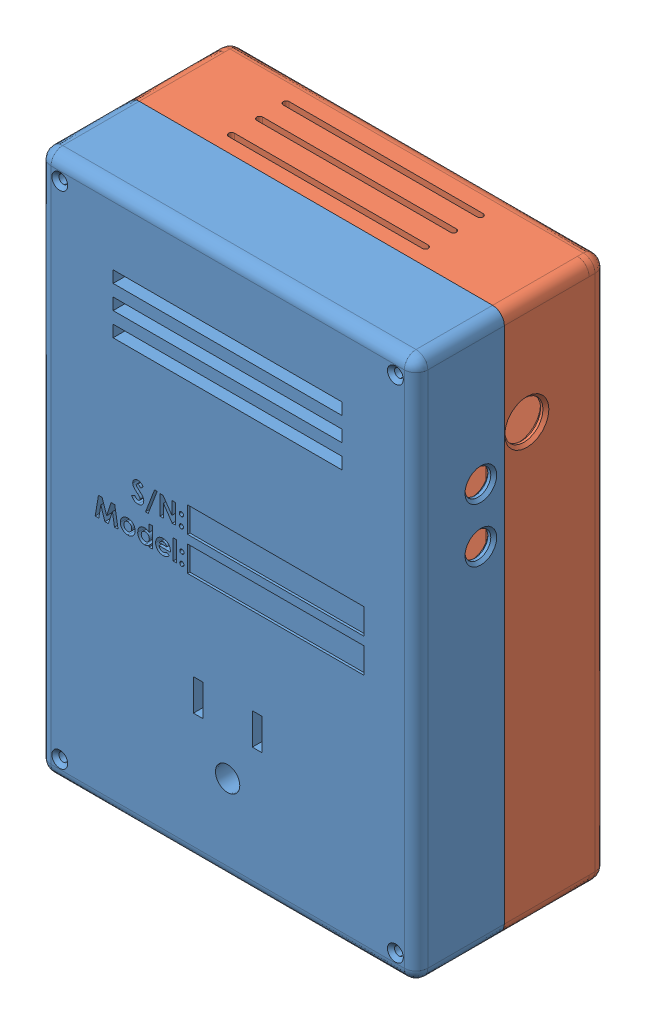
SolidWorks assembly Enclosure, configuration Default. Lengths in mm.
Overall size (81.28 116.84 41.15).
2 component instances, 2 part files, 3 mates.
Components (placement in the parent):
- back-1: back [Default] at (29.377 61.845 96.6049) size (81.28 116.84 19.05)
- front-1: front [Default] at (29.377 61.845 71.9669) x (-1 0 0) z (0 0 -1) size (81.28 116.84 24.13)
Mates (geometry in assembly coordinates):
- Coincident10: coincident anti-aligned: plane of back-1 through (29.377 61.845 90.2549) normal (0 0 -1); plane of front-1 through (29.377 61.845 90.2549) normal (0 0 1)
- Coincident11: coincident aligned: circle of back-1; circle of front-1
- Coincident12: coincident aligned: circle of back-1; circle of front-1
